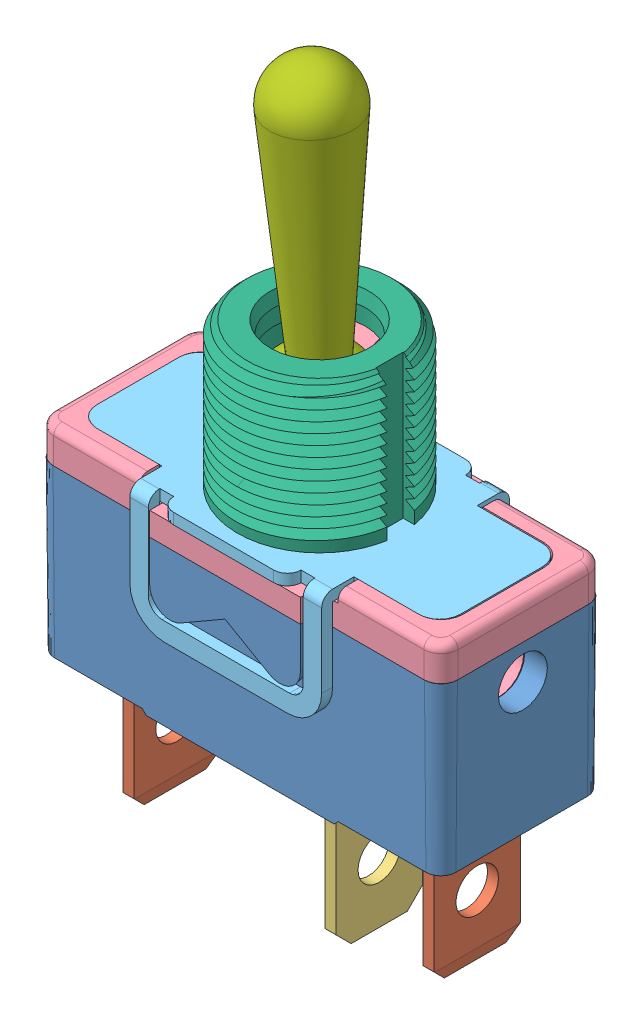
SolidWorks assembly 639H_SLASH_2 - SWITCH, TOGGLE, ON-OFF-ON, STD BAT, configuration 3WAY Mag Held - ON. Lengths in mm.
Overall size (29.5 52.64 14.05).
8 component instances, 7 part files, 4 mates.
Components (placement in the parent):
- 63-348-1: 63-348 [For 3WAY MAG HELD Switch] at origin size (29.5 13.9 14)
- 64-899-1: 64-899 [Default] at (10.55 2.3 -0.05) x (-1 0 0) z (0 0 -1)
- 64-899-2: 64-899 [Default] at (-10.55 2.3 -0.05)
- 264-34-0-1: 264-34-0 [Default] at (4.3 -10.73 0.05) x (0 0 1) z (-1 0 0)
- 63-94-1: 63-94 [For 3WAY MAG Held] at (0 12.5 0) size (29.5 18.7 14)
- 63-267-1: 63-267 [Default] at (-0.05 15 0.05)
- 63-97-1: 63-97 [Default] at (-0.05 15 0.05)
- 63-65-1: 63-65 [Default] at (0 19.8 0) x (0.999391 0.034899 0) z (0 0 1)
Mates (geometry in assembly coordinates):
- Angle1: planar angle = 1.53589 rad aligned: plane of 63-65-1 through (0 19.8 0) normal (0.999391 0.034899 0); plane of 63-267-1 through (-0.05 15 0.05) normal (0 1 0)
- Concentric2: concentric aligned: cylinder of 63-94-1 through (0 19.8 8.4) axis (0 0 1) radius 1.025; cylinder of 63-65-1 through (0 19.8 -4) axis (0 0 1) radius 1
- Width1: width aligned: plane of 63-94-1 through (-4.6259 23.2 2.375) normal (0 0 -1); plane of 63-65-1 through (4.6259 23.2 -2.375) normal (0 0 1); plane of 63-94-1 through (0.4188 7.8073 -2.25) normal (0 0 -1); plane of 63-65-1 through (0.4188 7.8073 2.25) normal (0 0 1)
- Concentric3: concentric aligned: circle of 63-97-1; cone of 63-65-1 through (-0.6541 38.5308 0) axis (0.034899 -0.999391 0)
